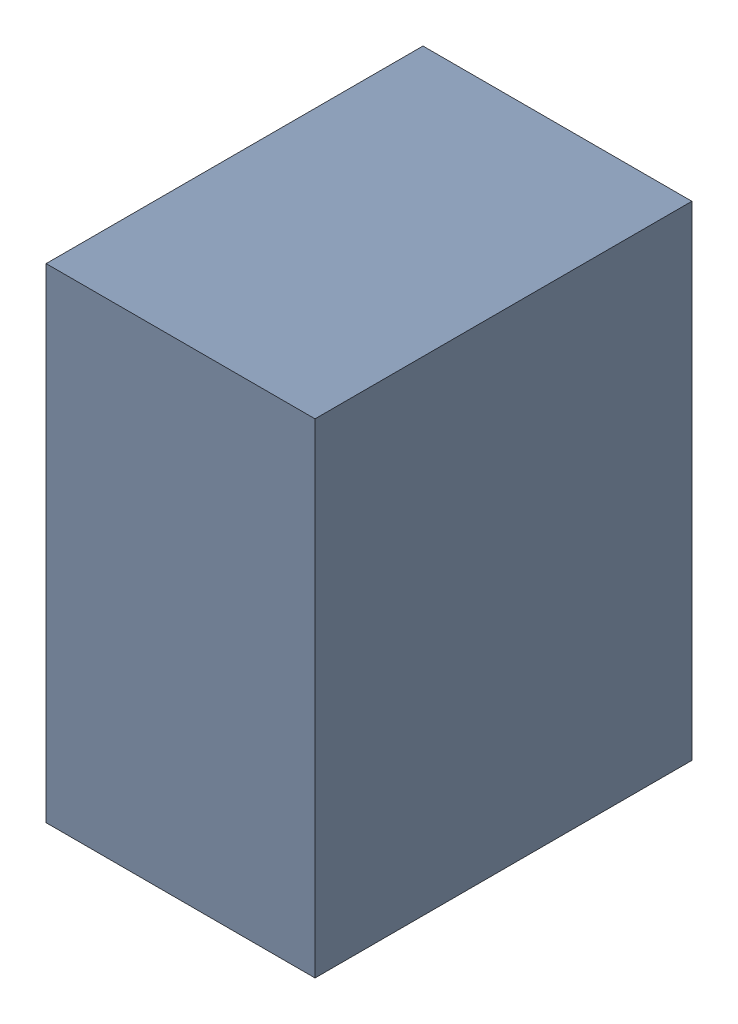
SolidWorks assembly C9, configuration Default. Lengths in mm.
Overall size (1 1.8 1.4).
3 component instances, 2 part files, 0 mates.
Components (placement in the parent):
- 1088883208-1: 1088883208 [Default] at (9.175 38.125 0) size (1 1.8 1.4)
  - Extruded-45-1: Extruded-45 [Default] at origin size (1 1.8 1.4)
- C0603-1: C0603 [Default] at (8.7749 38.925 0) x (0 -1 0) z (-1 0 0) size (1.6 0.5 0.8)
